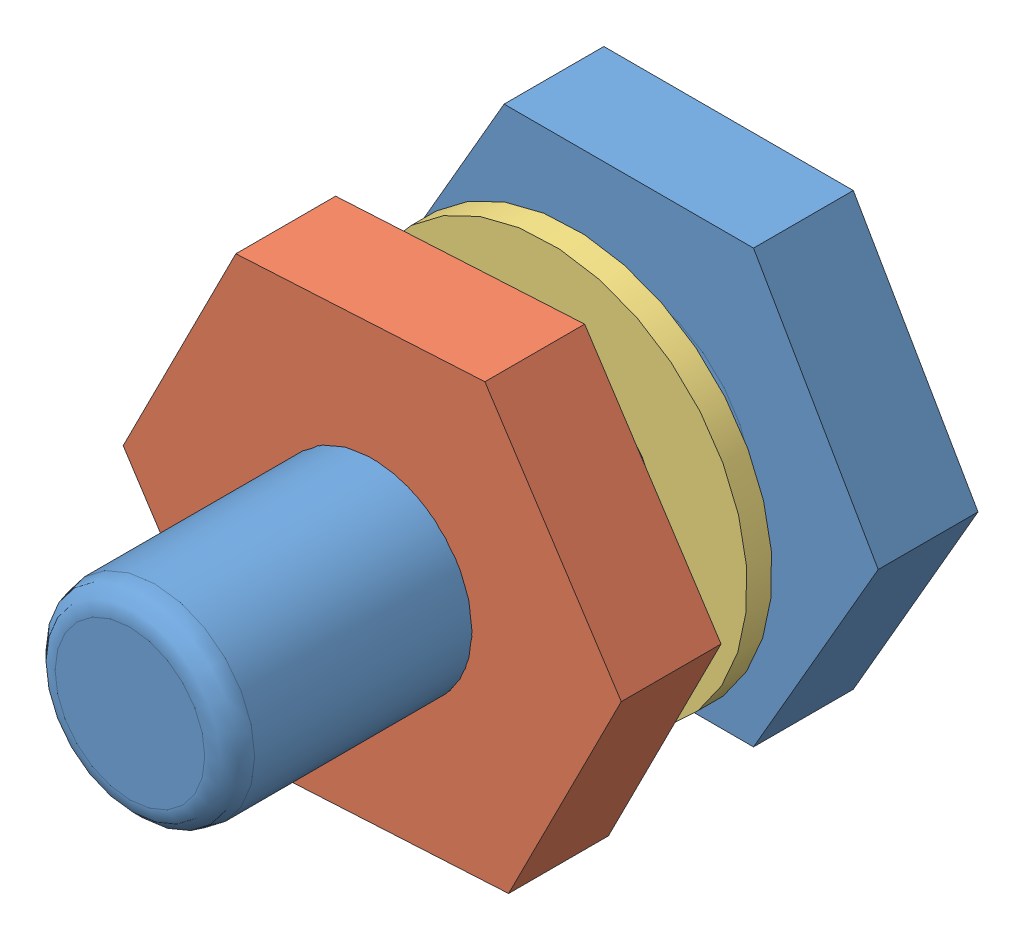
SolidWorks assembly practice nut washer bolt assembly, configuration Default. Lengths in mm.
Overall size (25.44 26.22 24).
3 component instances, 3 part files, 2 mates.
Components (placement in the parent):
- practice bolt-2: practice bolt [Default] at (8.8906 16.4553 3.7874) size (20 17.32 24)
- practice nut-1: practice nut [Default] at (8.8906 16.4553 14.0741) x (-0.546743 0.8373 0) z (0 0 1) size (20 17.32 4)
- practice washer-1: practice washer [Default] at (8.8906 16.4553 11.0372) x (0.043254 -0.999064 0) z (0 0 1) size (16 16 1)
Mates (geometry in assembly coordinates):
- Concentric2: concentric anti-aligned: cylinder of practice bolt-2 through (8.8906 16.4553 27.7874) axis (0 0 -1) radius 4; cylinder of practice nut-1 through (8.8906 16.4553 14.0741) axis (0 0 1) radius 4
- Concentric3: concentric anti-aligned: cylinder of practice bolt-2 through (8.8906 16.4553 27.7874) axis (0 0 -1) radius 4; circle of practice washer-1
